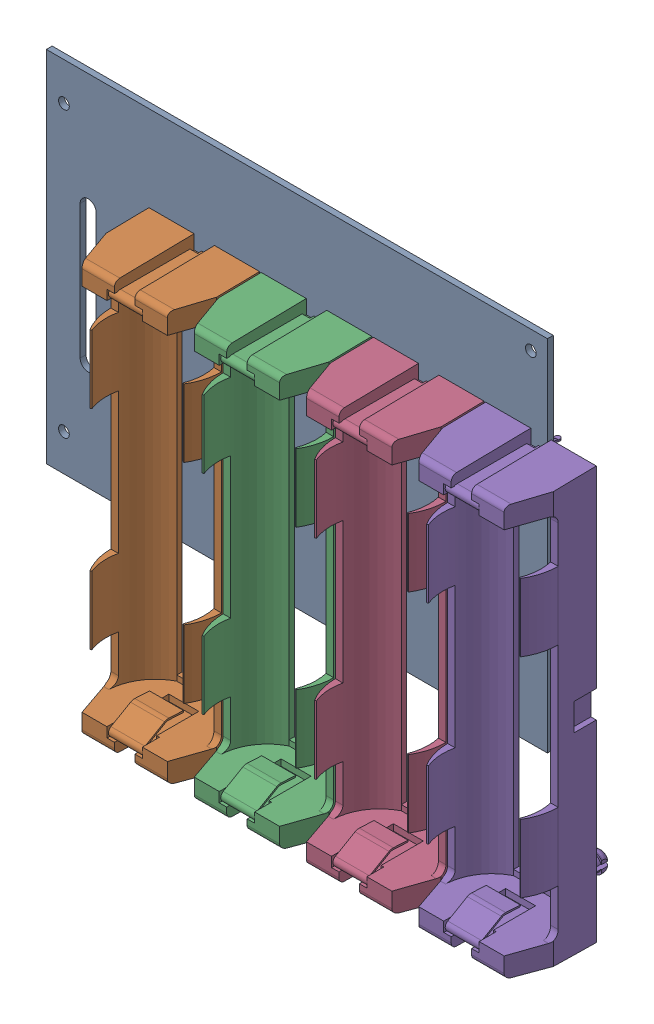
SolidWorks assembly Pedal_Power, configuration Default. Lengths in mm.
Overall size (102.68 93.06 18.41).
10 component instances, 2 part files, 0 mates.
Components (placement in the parent):
- Board-1: Board [Default] at origin size (93.55 66.99 1.09)
  - Open CASCADE STEP translator 7.5 5.1.1-1: Open CASCADE STEP translator 7.5 5.1.1 [Default] at (0 0 -1.0914) size (93.55 66.99 1.09)
- B4-1: B4 [Default] at origin size (20.65 77.05 18.41)
  - Keystone - PN1043-1: Keystone - PN1043 [Default] at (85.3725 59.8891 0) x (-1 0 0) z (0 0 1) size (20.65 77.05 18.41)
- B3-1: B3 [Default] at origin size (20.65 77.05 18.41)
  - Keystone - PN1043-1: Keystone - PN1043 [Default] at (106.3275 59.8891 0) x (-1 0 0) z (0 0 1) size (20.65 77.05 18.41)
- B2-1: B2 [Default] at origin size (20.65 77.05 18.41)
  - Keystone - PN1043-1: Keystone - PN1043 [Default] at (127.2825 59.8891 0) x (-1 0 0) z (0 0 1) size (20.65 77.05 18.41)
- B1-1: B1 [Default] at origin size (20.65 77.05 18.41)
  - Keystone - PN1043-1: Keystone - PN1043 [Default] at (148.2375 59.8891 0) x (-1 0 0) z (0 0 1) size (20.65 77.05 18.41)
